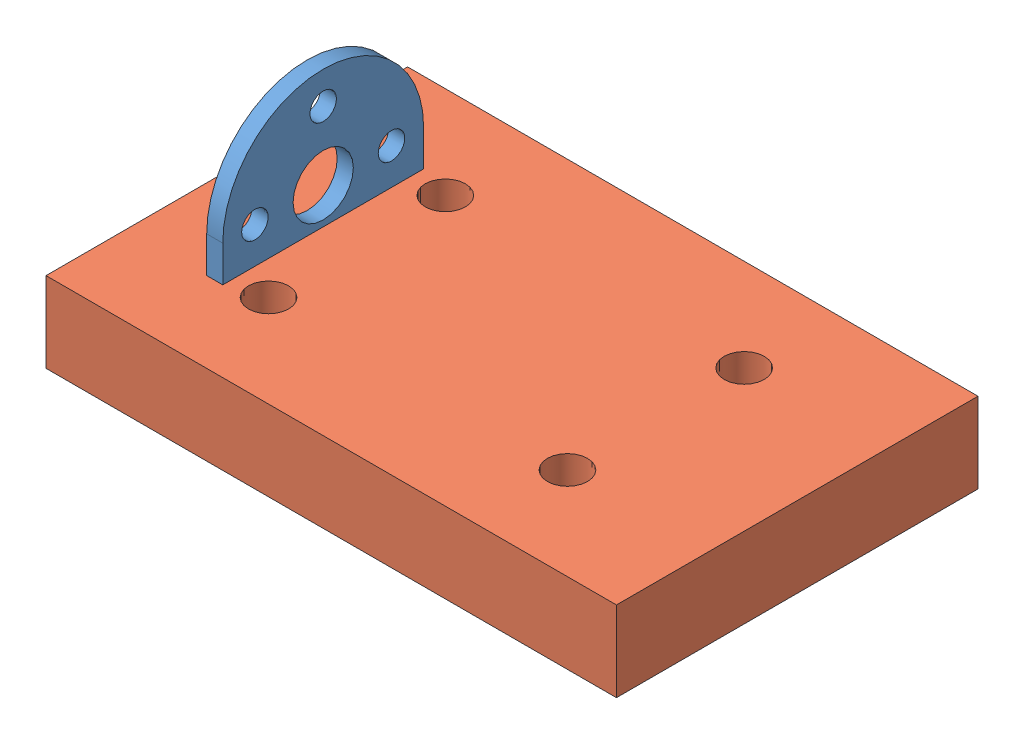
SolidWorks assembly Motor Jig, configuration Default. Lengths in mm.
Overall size (71 27 45).
2 component instances, 2 part files, 7 mates.
Components (placement in the parent):
- Pololu 25D mm Metal Gearmotor Bracket-1: Pololu 25D mm Metal Gearmotor Bracket [Default] at origin size (51 27 25)
- Motor Jig-1: Motor Jig [Default] x (1 0 0) z (0 1 0) size (71 45 10)
Mates (geometry in assembly coordinates):
- Coincident1: coincident aligned: plane of Pololu 25D mm Metal Gearmotor Bracket-1 through (0 0 0) normal (0 0 1)
- Coincident2: coincident aligned: plane of Pololu 25D mm Metal Gearmotor Bracket-1 through (0 0 0) normal (0 1 0)
- Coincident3: coincident aligned: plane of Pololu 25D mm Metal Gearmotor Bracket-1 through (0 0 0) normal (1 0 0)
- InPlace1: in place: plane of Motor Jig-1 through (0 0 0) normal (0 1 0); moOrthogonalPlaneRef_w of Motor Jig-1 through (0 0 0) normal (0 0 -1); plane of Motor Jig-1 through (0 0 0) normal (1 0 0); unknown of Motor Jig-1
- Coincident4: coincident aligned: 
- Coincident5: coincident aligned: plane of Motor Jig-1 through (0 0 0) normal (0 0 -1)
- Coincident6: coincident anti-aligned: plane of Motor Jig-1 through (0 0 0) normal (1 0 0)
